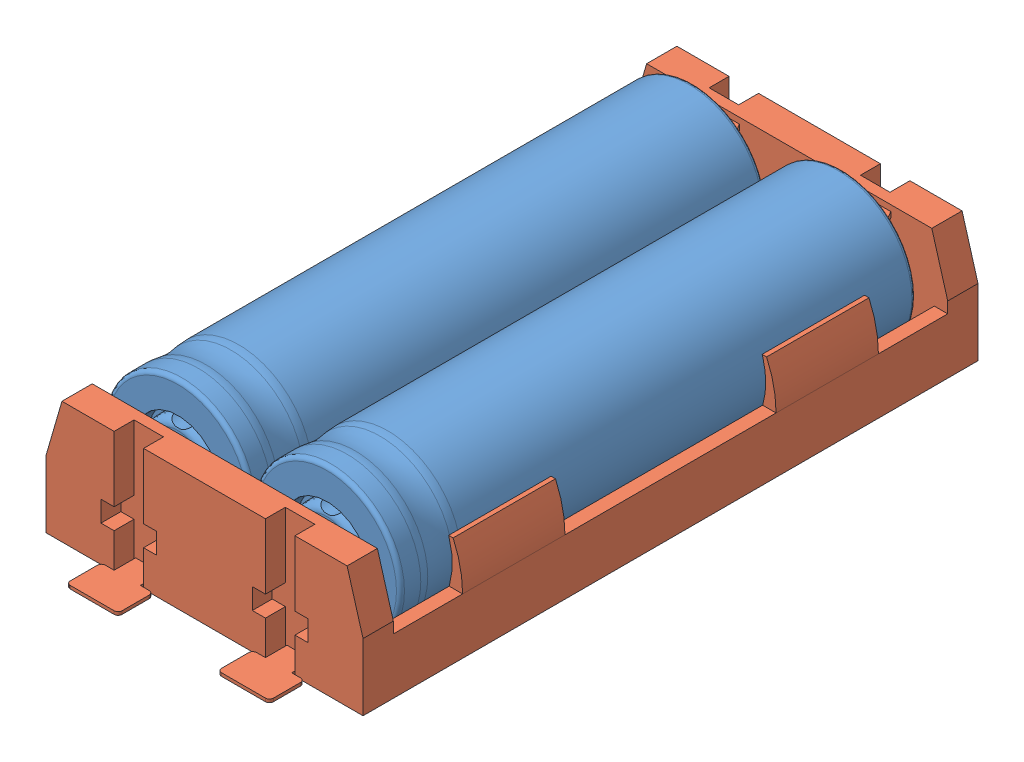
SolidWorks assembly Sestava1, configuration Výchozí. Lengths in mm.
Overall size (39.8 18.9 86.4).
3 component instances, 2 part files, 4 mates.
Components (placement in the parent):
- 18650 baterie-1: 18650 baterie [Výchozí] at (-5.3689 1.7057 32.3879) size (18.5 18.5 64.78)
- 18650 holder 2x-1: 18650 holder 2x [Výchozí] at (-14.7189 1.7057 25.8879) size (39.8 15.3 86.4)
- 18650 baterie-2: 18650 baterie [Výchozí] at (-24.0689 1.7057 32.3879) size (18.5 18.5 64.78)
Mates (geometry in assembly coordinates):
- Sjednocená1: coincident: plane of 18650 baterie-1 through (-5.3689 1.7057 97.0879) normal (0 0 1); plane of 18650 baterie-2 through (-24.0689 1.7057 97.0879) normal (0 0 1)
- Soustředná1: concentric: cylinder of 18650 baterie-1 through (-5.3689 1.7057 97.0879) axis (0 0 -1) radius 9.25; cylinder of 18650 holder 2x-1 through (-5.3689 1.7057 135.2813) axis (0 0 -1) radius 9.25
- Soustředná2: concentric: cylinder of 18650 holder 2x-1 through (-24.0689 1.7057 135.2813) axis (0 0 -1) radius 9.25; cylinder of 18650 baterie-2 through (-24.0689 1.7057 97.0879) axis (0 0 -1) radius 9.25
- Vzdálenost2: distance = 6 mm: plane of 18650 holder 2x-1 through (-14.7189 1.7057 103.0879) normal (0 0 1); plane of 18650 baterie-1 through (-5.3689 1.7057 97.0879) normal (0 0 1)
